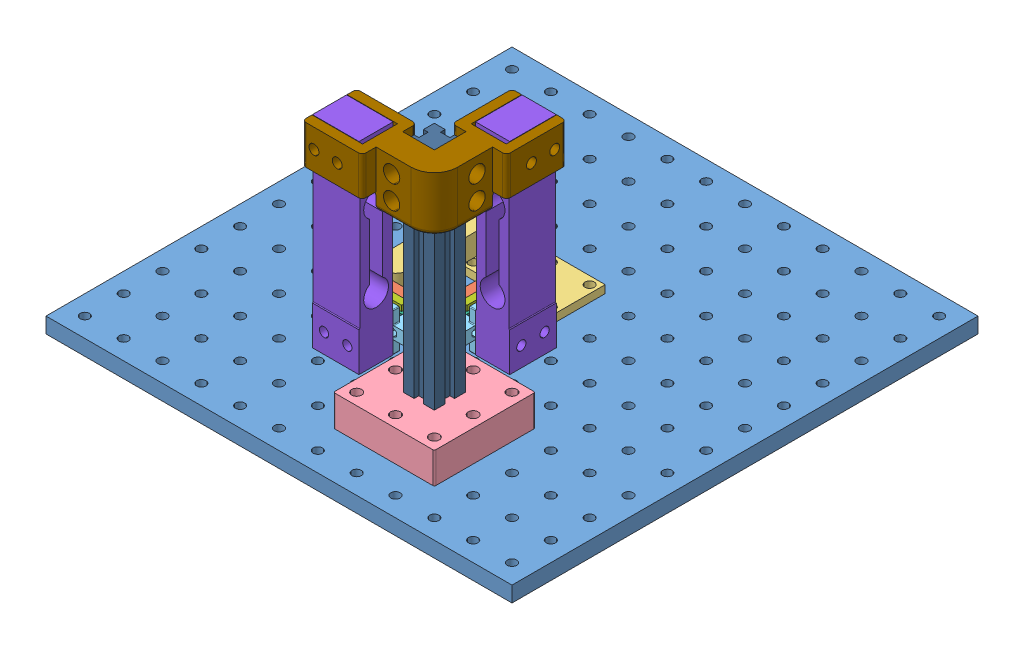
SolidWorks assembly 어셈블리2, configuration 기본. Lengths in mm.
Overall size (300 175.5 300).
14 component instances, 10 part files, 47 mates.
Components (placement in the parent):
- platform-1: platform [기본] at (-8.9522 -39.8142 300) size (300 10 300)
- contact_part_vertical-1: contact_part_vertical [기본] at (-5.0022 18.1858 353.95) x (0 0 -1) z (0 1 0) size (33.5 33.5 13)
- finger_model-1: finger_model [기본] at (-21.4522 -29.8142 287.5) size (60 55 113.75)
- linear_base-1: linear_base [기본] at (28.5478 -29.8142 387.5) x (-1 0 0) z (0 0 -1) size (65 20 65)
- linear_guide_holder_vertical_axis-1: linear_guide_holder_vertical_axis [기본] at (-5.0022 18.1858 395.45) x (0 1 0) z (0 0 -1) size (25 45 15)
- linear_guide_part1-1: linear_guide_part1 [기본] at (-5.0022 18.1858 380.95) x (1 0 0) z (0 -1 0) size (40 4 5)
- linear_guide_part2-1: linear_guide_part2 [기본] at (-5.0022 18.1858 383.55) x (1 0 0) z (0 1 0) size (17 4.6 12)
- Loadcell-1: Loadcell [기본] at (-20.0022 70.6858 406.45) x (0 1 0) z (1 0 0) size (130 22 30)
- Loadcell_holder_vertical_part1-1: Loadcell_holder_vertical_part1 [기본] at (47.4978 110.6858 406.45) size (85 35 85)
- profile_20x20x140-1: profile_20x20x140 [기본] at (28.5478 -9.8142 387.5) size (20 140 20)
- linear_guide_holder_vertical_axis-2: linear_guide_holder_vertical_axis [기본] at (36.4978 18.1858 353.95) x (0 -1 0) z (-1 0 0) size (25 45 15)
- linear_guide_part1-2: linear_guide_part1 [기본] at (21.9978 18.1858 353.95) x (0 0 1) z (0 1 0) size (40 4 5)
- linear_guide_part2-2: linear_guide_part2 [기본] at (24.5978 18.1858 353.95) x (0 0 -1) z (0 1 0) size (17 4.6 12)
- Loadcell-2: Loadcell [기본] at (47.4978 70.6858 338.95) x (0 1 0) z (0 0 1) size (130 22 30)
Mates (geometry in assembly coordinates):
- 일치1: coincident anti-aligned: plane of platform-1 through (-8.9522 -29.8142 300) normal (0 1 0); plane of finger_model-1 through (-21.4522 -29.8142 287.5) normal (0 -1 0)
- 동심1: concentric aligned: cylinder of finger_model-1 through (3.5478 -24.8142 287.5) axis (0 -1 0) radius 3; cylinder of platform-1 through (3.5478 -29.8142 287.5) axis (0 -1 0) radius 3
- 동심2: concentric aligned: cylinder of platform-1 through (-46.4522 -29.8142 262.5) axis (0 -1 0) radius 3; cylinder of finger_model-1 through (-46.4522 -24.8142 262.5) axis (0 -1 0) radius 3
- 일치2: coincident anti-aligned: plane of linear_base-1 through (28.5478 -9.8142 387.5) normal (0 1 0); plane of profile_20x20x140-1 through (28.5478 -9.8142 387.5) normal (0 -1 0)
- 너비1: width: plane of profile_20x20x140-1 through (31.5478 130.1858 397.5) normal (-1 0 0); plane of profile_20x20x140-1 through (25.5478 130.1858 397.5) normal (1 0 0); cylinder of linear_base-1 through (28.5478 -17.3142 362.5) axis (0 1 0) radius 3.2
- 너비3: width: plane of profile_20x20x140-1 through (18.5478 130.1858 384.5) normal (0 0 1); plane of profile_20x20x140-1 through (18.5478 130.1858 390.5) normal (0 0 -1); cylinder of linear_base-1 through (53.5478 -17.3142 387.5) axis (0 1 0) radius 3.2
- 너비4: width: plane of profile_20x20x140-1 through (38.5478 130.1858 384.5) normal (0 0 1); plane of profile_20x20x140-1 through (38.5478 130.1858 390.5) normal (0 0 -1); cylinder of Loadcell_holder_vertical_part1-1 through (29.8968 125.6858 387.5) axis (1 0 0) radius 3.2
- 너비5: width: plane of profile_20x20x140-1 through (31.5478 130.1858 397.5) normal (-1 0 0); plane of profile_20x20x140-1 through (25.5478 130.1858 397.5) normal (1 0 0); cylinder of Loadcell_holder_vertical_part1-1 through (28.5478 125.6858 388.849) axis (0 0 1) radius 3.2
- 너비6: width: plane of profile_20x20x140-1 through (25.5478 130.1858 397.5) normal (1 0 0); plane of profile_20x20x140-1 through (31.5478 130.1858 397.5) normal (-1 0 0); cylinder of linear_base-1 through (28.5478 -17.3142 412.5) axis (0 1 0) radius 3.2
- 너비7: width: plane of profile_20x20x140-1 through (18.5478 130.1858 384.5) normal (0 0 1); plane of profile_20x20x140-1 through (18.5478 130.1858 390.5) normal (0 0 -1); cylinder of linear_base-1 through (3.5478 -17.3142 387.5) axis (0 1 0) radius 3.2
- 동심3: concentric aligned: cylinder of Loadcell-1 through (-12.5022 123.1858 386.9647) axis (0 0 1) radius 3; cylinder of Loadcell_holder_vertical_part1-1 through (-12.5022 123.1858 379.899) axis (0 0 1) radius 3.2
- 동심4: concentric aligned: cylinder of Loadcell-1 through (2.4978 123.1858 386.9647) axis (0 0 1) radius 3; cylinder of Loadcell_holder_vertical_part1-1 through (2.4978 123.1858 379.899) axis (0 0 1) radius 3.2
- 너비8: width aligned: plane of Loadcell_holder_vertical_part1-1 through (9.9978 135.6858 395.2) normal (0 0 1); plane of Loadcell_holder_vertical_part1-1 through (-20.0022 135.6858 417.7) normal (0 0 -1); plane of Loadcell-1 through (9.9978 110.6858 417.45) normal (0 0 1); plane of Loadcell-1 through (9.9978 110.6858 395.45) normal (0 0 -1)
- 동심5: concentric aligned: cylinder of linear_guide_holder_vertical_axis-1 through (2.4978 18.1858 391.45) axis (0 0 1) radius 3.2; cylinder of Loadcell-1 through (2.4978 18.1858 386.9647) axis (0 0 1) radius 3
- 동심6: concentric aligned: cylinder of linear_guide_holder_vertical_axis-1 through (-12.5022 18.1858 391.45) axis (0 0 1) radius 3.2; cylinder of Loadcell-1 through (-12.5022 18.1858 386.9647) axis (0 0 1) radius 3
- 일치3: coincident anti-aligned: plane of linear_guide_holder_vertical_axis-1 through (-5.0022 18.1858 395.45) normal (0 0 1); plane of Loadcell-1 through (9.9978 5.6858 395.45) normal (0 0 -1)
- 일치4: coincident anti-aligned: plane of linear_guide_holder_vertical_axis-1 through (-5.0022 18.1858 384.95) normal (0 0 -1); plane of linear_guide_part1-1 through (-5.0022 18.1858 384.95) normal (0 0 1)
- 동심7: concentric anti-aligned: cylinder of linear_guide_holder_vertical_axis-1 through (-20.0022 18.1858 384.95) axis (0 0 1) radius 1.15; cylinder of linear_guide_part1-1 through (-20.0022 18.1858 384.95) axis (0 0 -1) radius 1.25
- 동심8: concentric anti-aligned: cylinder of linear_guide_holder_vertical_axis-1 through (-5.0022 18.1858 384.95) axis (0 0 1) radius 1.15; cylinder of linear_guide_part1-1 through (-5.0022 18.1858 384.95) axis (0 0 -1) radius 1.25
- 너비9: width anti-aligned: plane of linear_guide_part2-1 through (3.4978 20.6858 401.27) normal (0 -1 0); plane of linear_guide_part2-1 through (3.4978 15.6858 401.27) normal (0 1 0); plane of linear_guide_part1-1 through (14.9978 20.6858 384.95) normal (0 1 0); plane of linear_guide_part1-1 through (14.9978 15.6858 384.95) normal (0 -1 0)
- 일치5: coincident anti-aligned: plane of linear_guide_part1-1 through (-5.0022 18.1858 380.95) normal (0 0 -1); plane of linear_guide_part2-1 through (-5.0022 18.1858 380.95) normal (0 0 1)
- 평행2: parallel aligned: plane of Loadcell_holder_vertical_part1-1 through (47.4978 135.6858 406.45) normal (0 1 0); plane of profile_20x20x140-1 through (28.5478 130.1858 387.5) normal (0 1 0)
- 거리 한도1: limit distance = 11.7 mm anti-aligned: plane of linear_guide_holder_vertical_axis-1 through (-25.2022 14.1858 380.45) normal (1 0 0); plane of linear_guide_part2-1 through (-13.5022 12.1858 378.95) normal (-1 0 0)
- 거리 한도2: limit distance = 11.7 mm anti-aligned: plane of linear_guide_holder_vertical_axis-1 through (15.1978 14.1858 380.45) normal (-1 0 0); plane of linear_guide_part2-1 through (3.4978 12.1858 378.95) normal (1 0 0)
- 동심9: concentric anti-aligned: cylinder of contact_part_vertical-1 through (-5.0022 22.1858 372.65) axis (0 0 1) radius 1.15; cylinder of linear_guide_part2-1 through (-5.0022 22.1858 380.95) axis (0 0 -1) radius 1
- 동심10: concentric anti-aligned: cylinder of contact_part_vertical-1 through (-5.0022 14.1858 372.65) axis (0 0 1) radius 1.15; cylinder of linear_guide_part2-1 through (-5.0022 14.1858 380.95) axis (0 0 -1) radius 1
- 일치9: coincident anti-aligned: plane of contact_part_vertical-1 through (-5.0022 18.1858 378.95) normal (0 0 1); plane of linear_guide_part2-1 through (-5.0022 18.1858 378.95) normal (0 0 -1)
- 일치10: coincident anti-aligned: plane of platform-1 through (-8.9522 -29.8142 300) normal (0 1 0); plane of linear_base-1 through (28.5478 -29.8142 387.5) normal (0 -1 0)
- 동심11: concentric aligned: cylinder of platform-1 through (3.5478 -29.8142 362.5) axis (0 -1 0) radius 3; cylinder of linear_base-1 through (3.5478 -22.3142 362.5) axis (0 -1 0) radius 3
- 동심12: concentric aligned: cylinder of platform-1 through (53.5478 -29.8142 412.5) axis (0 -1 0) radius 3; cylinder of linear_base-1 through (53.5478 -22.3142 412.5) axis (0 -1 0) radius 3
- 너비10: width: plane of finger_model-1 through (-21.4522 25.1858 287.5) normal (0 1 0); plane of finger_model-1 through (-21.4522 11.1858 287.5) normal (0 -1 0); cylinder of contact_part_vertical-1 through (27.0688 18.1858 353.95) axis (-1 0 0) radius 2.5
- 너비11: width anti-aligned: plane of Loadcell_holder_vertical_part1-1 through (36.2478 135.6858 338.95) normal (1 0 0); plane of Loadcell_holder_vertical_part1-1 through (58.7478 135.6858 368.95) normal (-1 0 0); plane of Loadcell-2 through (36.4978 110.6858 368.95) normal (-1 0 0); plane of Loadcell-2 through (58.4978 110.6858 368.95) normal (1 0 0)
- 동심13: concentric anti-aligned: cylinder of Loadcell_holder_vertical_part1-1 through (20.9468 123.1858 361.45) axis (1 0 0) radius 3.2; cylinder of Loadcell-2 through (66.9831 123.1858 361.45) axis (-1 0 0) radius 3
- 동심14: concentric anti-aligned: cylinder of Loadcell_holder_vertical_part1-1 through (20.9468 123.1858 346.45) axis (1 0 0) radius 3.2; cylinder of Loadcell-2 through (66.9831 123.1858 346.45) axis (-1 0 0) radius 3
- 동심15: concentric anti-aligned: cylinder of linear_guide_holder_vertical_axis-2 through (32.4978 18.1858 361.45) axis (1 0 0) radius 3.2; cylinder of Loadcell-2 through (66.9831 18.1858 361.45) axis (-1 0 0) radius 3
- 동심16: concentric anti-aligned: cylinder of linear_guide_holder_vertical_axis-2 through (32.4978 18.1858 346.45) axis (1 0 0) radius 3.2; cylinder of Loadcell-2 through (66.9831 18.1858 346.45) axis (-1 0 0) radius 3
- 일치11: coincident anti-aligned: plane of linear_guide_holder_vertical_axis-2 through (36.4978 18.1858 353.95) normal (1 0 0); plane of Loadcell-2 through (36.4978 5.6858 368.95) normal (-1 0 0)
- 동심17: concentric anti-aligned: cylinder of linear_guide_holder_vertical_axis-2 through (25.9978 18.1858 368.95) axis (1 0 0) radius 1.15; cylinder of linear_guide_part1-2 through (25.9978 18.1858 368.95) axis (-1 0 0) radius 1.25
- 동심18: concentric anti-aligned: cylinder of linear_guide_holder_vertical_axis-2 through (25.9978 18.1858 338.95) axis (1 0 0) radius 1.15; cylinder of linear_guide_part1-2 through (25.9978 18.1858 338.95) axis (-1 0 0) radius 1.25
- 일치12: coincident anti-aligned: plane of linear_guide_holder_vertical_axis-2 through (25.9978 18.1858 353.95) normal (-1 0 0); plane of linear_guide_part1-2 through (25.9978 18.1858 353.95) normal (1 0 0)
- 너비12: width anti-aligned: plane of linear_guide_part1-2 through (25.9978 20.6858 373.95) normal (0 1 0); plane of linear_guide_part1-2 through (25.9978 15.6858 373.95) normal (0 -1 0); plane of linear_guide_part2-2 through (42.3178 20.6858 345.45) normal (0 -1 0); plane of linear_guide_part2-2 through (42.3178 15.6858 345.45) normal (0 1 0)
- 일치13: coincident anti-aligned: plane of linear_guide_part1-2 through (21.9978 18.1858 353.95) normal (-1 0 0); plane of linear_guide_part2-2 through (21.9978 18.1858 353.95) normal (1 0 0)
- 거리 한도3: limit distance = 11.7 mm anti-aligned: plane of linear_guide_holder_vertical_axis-2 through (21.4978 22.1858 333.75) normal (0 0 1); plane of linear_guide_part2-2 through (19.9978 12.1858 345.45) normal (0 0 -1)
- 거리 한도4: limit distance = 11.7 mm anti-aligned: plane of linear_guide_holder_vertical_axis-2 through (21.4978 22.1858 374.15) normal (0 0 -1); plane of linear_guide_part2-2 through (19.9978 12.1858 362.45) normal (0 0 1)
- 동심19: concentric anti-aligned: cylinder of contact_part_vertical-1 through (13.6978 22.1858 353.95) axis (1 0 0) radius 1.15; cylinder of linear_guide_part2-2 through (21.9978 22.1858 353.95) axis (-1 0 0) radius 1
- 동심20: concentric anti-aligned: cylinder of contact_part_vertical-1 through (13.6978 14.1858 353.95) axis (1 0 0) radius 1.15; cylinder of linear_guide_part2-2 through (21.9978 14.1858 353.95) axis (-1 0 0) radius 1
- 일치15: coincident anti-aligned: plane of contact_part_vertical-1 through (19.9978 18.1858 353.95) normal (1 0 0); plane of linear_guide_part2-2 through (19.9978 18.1858 353.95) normal (-1 0 0)
